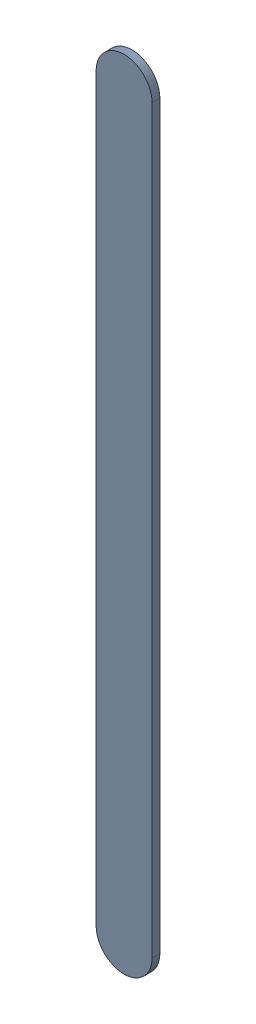
SolidWorks assembly Track (29.2mm,9.134mm)(29.2mm,12.5mm) on Top Layer, configuration Predeterminado. Lengths in mm.
Overall size (0.25 3.62 0.04).
2 component instances, 1 part files, 0 mates.
Components (placement in the parent):
- Track (29.2mm,9.134mm)(29.2mm,12.5mm) on Top Layer-1-1: Track (29.2mm,9.134mm)(29.2mm,12.5mm) on Top Layer-1 [Predeterminado] at (-68.317 -44.187 -0.0457) size (0.25 3.62 0.04)
  - Track (29.2mm,9.134mm)(29.2mm,12.5mm) on Top Layer-Part-1-1: Track (29.2mm,9.134mm)(29.2mm,12.5mm) on Top Layer-Part-1 [Predeterminado] at origin size (0.25 3.62 0.04)
